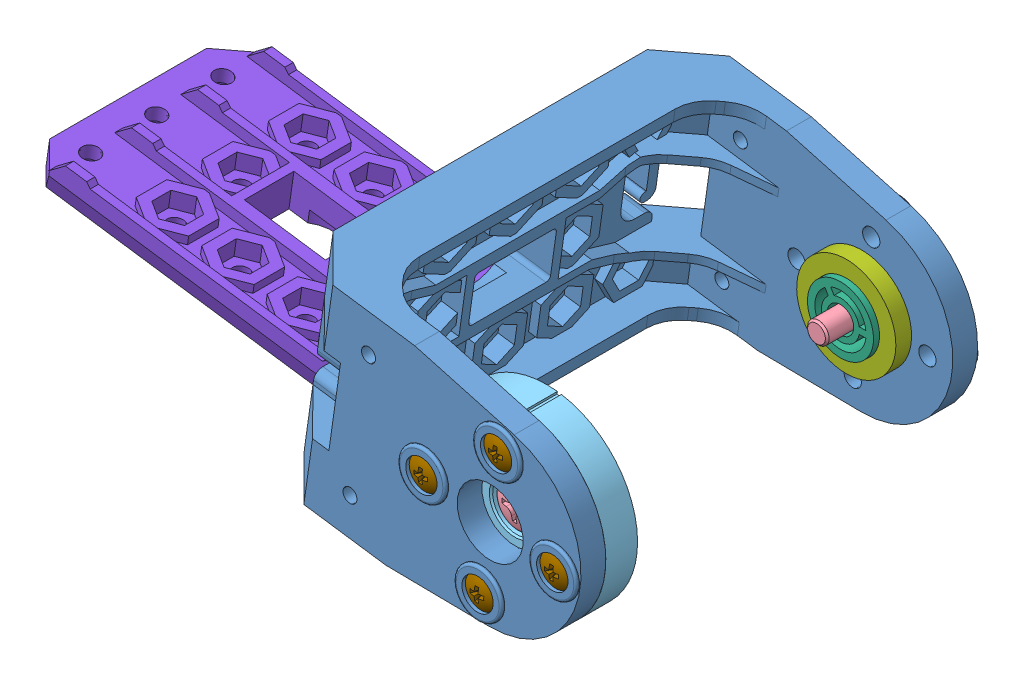
SolidWorks assembly main, configuration Défaut. Lengths in mm.
Overall size (80.88 29.94 50.08).
18 component instances, 9 part files, 28 mates.
Components (placement in the parent):
- F2-1: F2 [Défaut] at (-0.5061 -4.7478 -8.6716) x (0 0 1) z (-0.990114 0.140262 0) size (48.8 25 37)
- ASSY_GEAR-WHEEL___DUMMY-1: ASSY_GEAR-WHEEL___DUMMY [Défaut] at (-0.5061 -4.7478 -8.6116) size (6.5 6.5 5.51)
- BHS_M2_6X8-1: BHS_M2_6X8 [Défaut] at (-0.5061 -4.7478 -8.5416) size (5.92 5.92 9.6)
  - BHS_M2_6X8-1: BHS_M2_6X8 [Défaut] at origin size (2.15 2.15 8)
  - BHS_M2_6X8-1-1: BHS_M2_6X8-1 [Défaut] at origin size (5.92 5.92 9.6)
- DC04_B01_HORN2_DUMMY-1: DC04_B01_HORN2_DUMMY [Défaut] at (-0.5061 -4.7478 -8.5416) x (0.990114 -0.140262 0) z (0 0 1) size (22 22 6.71)
- BU-1: BU [Défaut] at (-0.5061 -4.7478 -27.0716) x (1 0 0) z (0 1 0) size (10 7.1 10)
- WA-1: WA [Défaut] at (-0.5061 -4.7478 -29.6716) x (1 0 0) z (0 -1 0) size (12 1.9 12)
- BHS_M2_6X8-3: BHS_M2_6X8 [Défaut] at (-0.5061 -4.7478 -12.6916) x (0.923728 0.383049 0) z (0 0 -1) size (5.92 5.92 9.6)
  - BHS_M2_6X8-1: BHS_M2_6X8 [Défaut] at origin size (2.15 2.15 8)
  - BHS_M2_6X8-1-1: BHS_M2_6X8-1 [Défaut] at origin size (5.92 5.92 9.6)
- F6-1: F6 [Défaut] at (-31.1129 -14.0468 -8.6716) x (0.990114 -0.140262 0) z (0 0 1) size (41 9 25)
- vis M2-1: vis M2 [B18.6.7M - M2 x 0.4 x 2.5 Type I Cross Recessed PHMS --2.5N] at (-1.6282 -12.6688 15.9284) x (0 0 -1) z (1 0 0) size (4.08 4 4)
- vis M2-2: vis M2 [B18.6.7M - M2 x 0.4 x 2.5 Type I Cross Recessed PHMS --2.5N] at (7.4148 -5.8699 15.9284) x (0 0 -1) z (1 0 0) size (4.08 4 4)
- vis M2-3: vis M2 [B18.6.7M - M2 x 0.4 x 2.5 Type I Cross Recessed PHMS --2.5N] at (-8.427 -3.6258 15.9284) x (0 0 -1) z (1 0 0) size (4.08 4 4)
- vis M2-4: vis M2 [B18.6.7M - M2 x 0.4 x 2.5 Type I Cross Recessed PHMS --2.5N] at (0.616 3.1731 15.9284) x (0 0 -1) z (1 0 0) size (4.08 4 4)
- vis M2-5: vis M2 [B18.6.7M - M2 x 0.4 x 2.5 Type I Cross Recessed PHMS --2.5N] at (-31.9257 -8.3767 -0.6716) x (0.990114 -0.140262 0) z (0.019673 0.138875 0.990114) size (4.08 4 4)
- vis M2-6: vis M2 [B18.6.7M - M2 x 0.4 x 2.5 Type I Cross Recessed PHMS --2.5N] at (-31.9257 -8.3767 -16.6716) x (0.990114 -0.140262 0) z (0.019673 0.138875 0.990114) size (4.08 4 4)
Mates (geometry in assembly coordinates):
- Coaxiale2: concentric anti-aligned: cylinder of ASSY_GEAR-WHEEL___DUMMY-1 through (-0.5061 -4.7478 5.2884) axis (0 0 1) radius 2.9; cylinder of DC04_B01_HORN2_DUMMY-1 through (-0.5061 -4.7478 9.2884) axis (0 0 -1) radius 2.95
- Coïncidente2: coincident anti-aligned: plane of ASSY_GEAR-WHEEL___DUMMY-1 through (-3.1063 -7.3473 9.2884) normal (0 0 1); plane of DC04_B01_HORN2_DUMMY-1 through (-3.1134 -1.2799 9.2884) normal (0 0 -1)
- Coaxiale3: concentric aligned: cylinder of BHS_M2_6X8-1/BHS_M2_6X8-1-1 through (-0.5061 -4.7478 10.9384) axis (0 0 -1) radius 1.3; cylinder of DC04_B01_HORN2_DUMMY-1 through (-0.5061 -4.7478 10.9384) axis (0 0 -1) radius 1.3
- Coïncidente3: coincident anti-aligned: plane of BHS_M2_6X8-1/BHS_M2_6X8-1-1 through (-2.9793 -2.2746 10.9384) normal (0 0 -1); plane of DC04_B01_HORN2_DUMMY-1 through (-3.0929 -1.4913 10.9384) normal (0 0 1)
- Coïncidente4: coincident anti-aligned: plane of DC04_B01_HORN2_DUMMY-1 through (-10.2316 8.1812 12.3284) normal (0 0 1); plane of F2-1 through (-18.8538 10.9811 12.3284) normal (0 0 -1)
- Coaxiale4: concentric anti-aligned: cylinder of DC04_B01_HORN2_DUMMY-1 through (-8.427 -3.6258 10.4884) axis (0 0 1) radius 1.05; cylinder of F2-1 through (-8.427 -3.6258 14.3284) axis (0 0 -1) radius 1.05
- Coaxiale5: concentric anti-aligned: cone of DC04_B01_HORN2_DUMMY-1 through (-0.5061 -4.7478 12.1284) axis (0 0 -1); cylinder of F2-1 through (-0.5061 -4.7478 12.3284) axis (0 0 1) radius 4
- Coaxiale12: concentric anti-aligned: cylinder of F2-1 through (-1.6282 -12.6688 14.3284) axis (0 0 -1) radius 1.05; cylinder of vis M2-1 through (-1.6282 -12.6688 41.3284) axis (0 0 1) radius 1
- Coïncidente6: coincident anti-aligned: plane of F2-1 through (8.244 -16.3862 14.3284) normal (0 0 1); plane of vis M2-1 through (-1.6282 -11.6688 14.3284) normal (0 0 -1)
- Coaxiale13: concentric anti-aligned: cylinder of F2-1 through (7.4148 -5.8699 14.3284) axis (0 0 -1) radius 1.05; cylinder of vis M2-2 through (7.4148 -5.8699 41.3284) axis (0 0 1) radius 1
- Coïncidente7: coincident anti-aligned: plane of F2-1 through (8.244 -16.3862 14.3284) normal (0 0 1); plane of vis M2-2 through (7.4148 -4.8699 14.3284) normal (0 0 -1)
- Coaxiale14: concentric anti-aligned: cylinder of F2-1 through (-8.427 -3.6258 14.3284) axis (0 0 -1) radius 1.05; cylinder of vis M2-3 through (-8.427 -3.6258 41.3284) axis (0 0 1) radius 1
- Coïncidente8: coincident anti-aligned: plane of F2-1 through (8.244 -16.3862 14.3284) normal (0 0 1); plane of vis M2-3 through (-8.427 -2.6258 14.3284) normal (0 0 -1)
- Coaxiale15: concentric anti-aligned: cylinder of F2-1 through (0.616 3.1731 14.3284) axis (0 0 -1) radius 1.05; cylinder of vis M2-4 through (0.616 3.1731 41.3284) axis (0 0 1) radius 1
- Coïncidente9: coincident anti-aligned: plane of F2-1 through (8.244 -16.3862 14.3284) normal (0 0 1); plane of vis M2-4 through (0.616 4.1731 14.3284) normal (0 0 -1)
- Coaxiale18: concentric anti-aligned: cylinder of F2-1 through (-0.5061 -4.7478 -32.6716) axis (0 0 1) radius 4; cylinder of BU-1 through (-0.5061 -4.7478 -27.0716) axis (0 0 -1) radius 4
- Coïncidente12: coincident anti-aligned: plane of F2-1 through (-20.1087 11.1589 -32.6716) normal (0 0 -1); plane of BU-1 through (-0.5061 -4.7478 -32.6716) normal (0 0 1)
- Coaxiale19: concentric anti-aligned: cylinder of BU-1 through (-0.5061 -4.7478 -27.0716) axis (0 0 -1) radius 4; cylinder of WA-1 through (-0.5061 -4.7478 -29.6716) axis (0 0 1) radius 4.025
- Coïncidente13: coincident anti-aligned: plane of F2-1 through (-18.8538 10.9811 -29.6716) normal (0 0 1); plane of WA-1 through (5.4939 -4.7478 -29.6716) normal (0 0 -1)
- Coaxiale21: concentric anti-aligned: cylinder of BU-1 through (-0.5061 -4.7478 -34.1716) axis (0 0 -1) radius 1.6; cylinder of BHS_M2_6X8-3/BHS_M2_6X8-1-1 through (-0.5061 -4.7478 -32.1716) axis (0 0 1) radius 1.3
- Coïncidente14: coincident anti-aligned: plane of BU-1 through (1.0939 -4.7478 -32.1716) normal (0 0 -1); plane of BHS_M2_6X8-3/BHS_M2_6X8-1-1 through (-1.8433 -7.9798 -32.1716) normal (0 0 1)
- Coïncidente15: coincident anti-aligned: plane of F2-1 through (-24.4256 11.7705 -28.4316) normal (-0.990114 0.140262 0); plane of F6-1 through (-26.862 -5.4278 4.3284) normal (0.990114 -0.140262 0)
- Coaxiale22: concentric anti-aligned: cylinder of F2-1 through (-25.3909 -9.3025 -0.6716) axis (-0.990114 0.140262 0) radius 1.05; cylinder of F6-1 through (-27.3711 -9.022 -0.6716) axis (0.990114 -0.140262 0) radius 1.05
- Coaxiale23: concentric anti-aligned: cylinder of F2-1 through (-25.3909 -9.3025 -16.6716) axis (-0.990114 0.140262 0) radius 1.05; cylinder of F6-1 through (-27.3711 -9.022 -16.6716) axis (0.990114 -0.140262 0) radius 1.05
- Coaxiale24: concentric anti-aligned: cylinder of vis M2-6 through (-57.0746 -4.8141 -16.6716) axis (-0.990114 0.140262 0) radius 1; cylinder of F6-1 through (-27.3711 -9.022 -16.6716) axis (0.990114 -0.140262 0) radius 1.05
- Coaxiale25: concentric anti-aligned: cylinder of vis M2-5 through (-57.0746 -4.8141 -0.6716) axis (-0.990114 0.140262 0) radius 1; cylinder of F6-1 through (-27.3711 -9.022 -0.6716) axis (0.990114 -0.140262 0) radius 1.05
- Coïncidente16: coincident anti-aligned: plane of vis M2-6 through (-30.2026 -7.6208 -16.8119) normal (0.990114 -0.140262 0); plane of F6-1 through (-29.8365 -5.0368 4.2244) normal (-0.990114 0.140262 0)
- Coïncidente17: coincident anti-aligned: plane of vis M2-5 through (-30.2026 -7.6208 -0.8119) normal (0.990114 -0.140262 0); plane of F6-1 through (-29.8365 -5.0368 4.2244) normal (-0.990114 0.140262 0)
